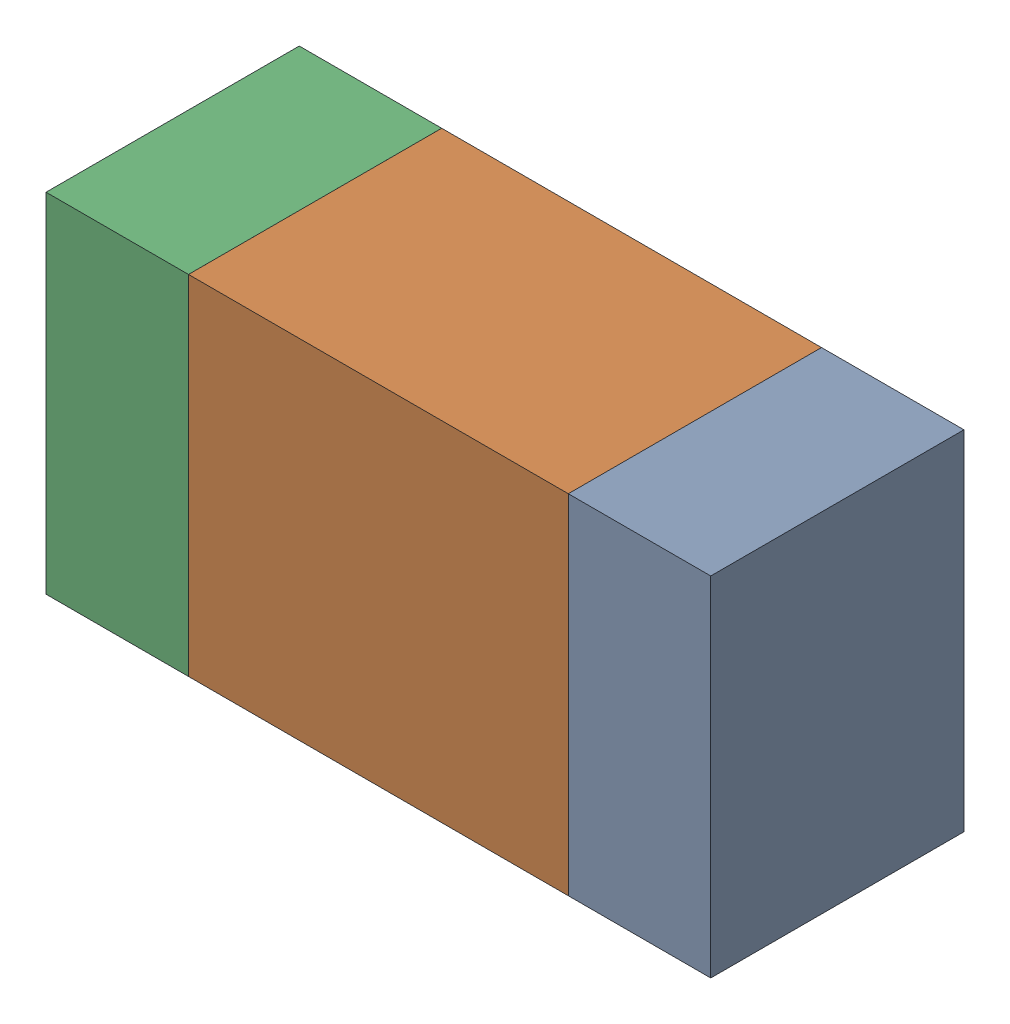
SolidWorks assembly R318_1PCB, configuration Default. Lengths in mm.
Overall size (1.05 0.55 0.4).
6 component instances, 2 part files, 0 mates.
Components (placement in the parent):
- 854785432-1: 854785432 [Default] at (136.0124 110.6999 -2.0638) size (0.22 0.55 0.4)
  - Extruded-1: Extruded [Default] at origin size (0.22 0.55 0.4)
- 854785568-1: 854785568 [Default] at (135.5999 110.6999 -2.0638) size (0.6 0.55 0.4)
  - Extruded_2-1: Extruded_2 [Default] at origin size (0.6 0.55 0.4)
- 854785432-2: 854785432 [Default] at (135.1874 110.6999 -2.0638) size (0.22 0.55 0.4)
  - Extruded-1: Extruded [Default] at origin size (0.22 0.55 0.4)
